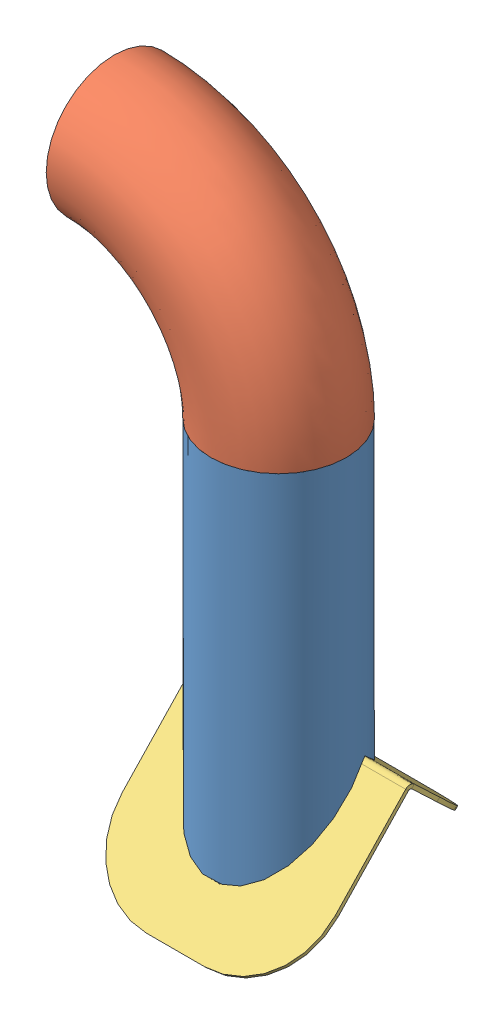
SolidWorks assembly Assembled Filler Tube, configuration Default. Lengths in mm.
Overall size (89.72 236.07 70.15).
3 component instances, 3 part files, 6 mates.
Components (placement in the parent):
- Filler Tube-2: Filler Tube [Default] at (-0.825 -44.614 8.9531) size (44.45 119.98 44.45)
- Filler Tube Bend-2: Filler Tube Bend [Default] at (-0.825 76.036 8.9531) size (76.2 76.2 44.45)
- Filler Tube Flange-2: Filler Tube Flange [Default] at (-34.925 -40.54 -25.632) x (1 0 0) z (0 -0.68846 -0.725275) size (69.85 60.96 38.86)
Mates (geometry in assembly coordinates):
- Coincident4: coincident anti-aligned: plane of Filler Tube-2 through (-23.05 -43.9403 31.1781) normal (0 -0.68846 -0.725275); plane of Filler Tube Flange-2 through (-34.925 -13.7851 2.5536) normal (0 0.68846 0.725275)
- Coincident6: coincident anti-aligned: plane of Filler Tube-2 through (-23.05 -12.864 1.6792) normal (0 -0.725275 0.68846); plane of Filler Tube Flange-2 through (-34.925 -12.864 1.6792) normal (0 0.725275 -0.68846)
- Distance2: distance = 34.925 mm aligned: plane of Filler Tube Flange-2 through (34.925 -13.7851 2.5536) normal (1 0 0); plane of assembly through (0 0 0) normal (1 0 0)
- Coincident10: coincident anti-aligned: plane of Filler Tube-2 through (-0.825 76.036 -11.6209) normal (0 1 0); plane of Filler Tube Bend-2 through (-0.825 76.036 8.9531) normal (0 -1 0)
- Coincident11: coincident anti-aligned: circle of Filler Tube-2; circle of Filler Tube Bend-2
- Coincident12: coincident aligned: plane of Filler Tube-2 through (-0.825 -44.614 8.9531) normal (0 0 1); plane of Filler Tube Bend-2 through (-0.825 76.036 8.9531) normal (0 0 1)
